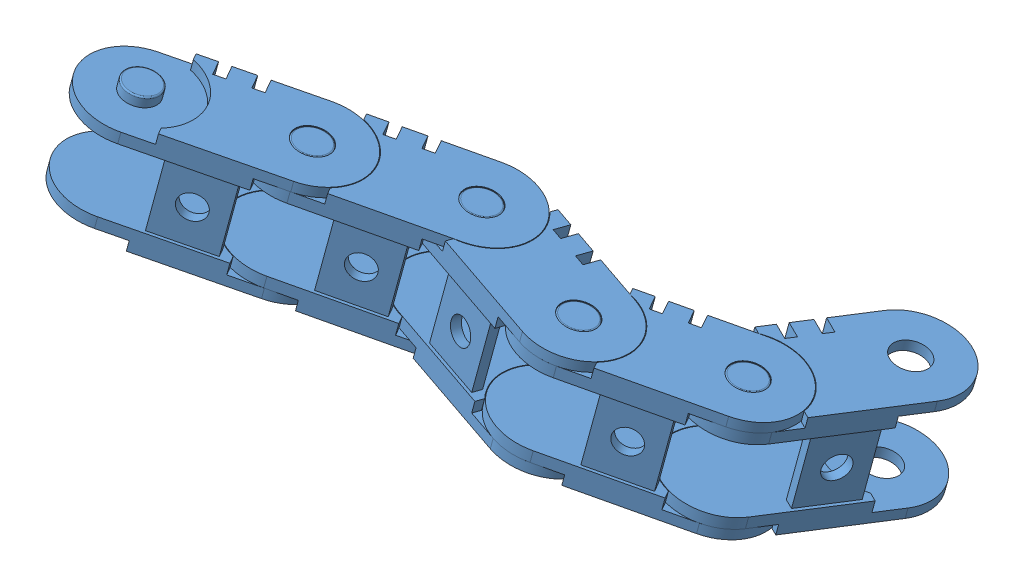
SolidWorks assembly energy chain, configuration Default. Lengths in mm.
Overall size (69.44 28.58 44.53).
5 component instances, 1 part files, 12 mates.
Components (placement in the parent):
- clen-6: clen [25x25] at (186.9346 0.4936 -8.835) x (0.848324 -0.220855 -0.481216) z (0.486505 -0.033523 0.873034) size (32.4 16.08 14)
- clen-7: clen [25x25] at (198.6906 -2.5591 -15.4058) x (0.853174 -0.221181 -0.472412) z (0.47795 -0.031301 0.877829) size (32.4 16.08 14)
- clen-8: clen [25x25] at (211.9978 -5.4844 -16.3032) x (0.960789 -0.189554 0.202369) z (-0.182278 0.118195 0.976117) size (32.4 16.08 14)
- clen-9: clen [25x25] at (223.7233 -8.2272 -19.1324) x (0.853174 -0.221181 -0.472412) z (0.47795 -0.031301 0.877829) size (32.4 16.08 14)
- clen-10: clen [25x25] at (230.7937 -10.5439 -29.0146) x (0.346349 -0.149315 -0.926147) z (0.91454 -0.16615 0.368795) size (32.4 16.08 14)
Mates (geometry in assembly coordinates):
- Concentric6: concentric anti-aligned: cylinder of clen-6 through (189.7699 -10.7257 -9.7667) axis (-0.208946 -0.97473 0.079009) radius 1.8075; cylinder of clen-7 through (189.5442 -11.7787 -9.6813) axis (0.208946 0.97473 -0.079009) radius 1.8
- Coincident12: coincident aligned: plane of clen-6 through (178.063 -7.6782 -3.1259) normal (0.208946 0.97473 -0.079009); plane of clen-7 through (189.7698 -10.726 -9.7666) normal (0.208946 0.97473 -0.079009)
- LimitAngle6: limit planar angle = 0.010056 rad aligned: plane of clen-6 through (175.5088 -7.5022 -7.7093) normal (-0.486505 0.033523 -0.873034); plane of clen-7 through (187.2606 -10.5616 -14.3752) normal (-0.47795 0.031301 -0.877829)
- Concentric7: concentric anti-aligned: cylinder of clen-7 through (201.5437 -13.778 -16.2859) axis (-0.208946 -0.97473 0.079009) radius 1.8075; cylinder of clen-8 through (201.318 -14.831 -16.2006) axis (0.208946 0.97473 -0.079009) radius 1.8
- Coincident13: coincident aligned: plane of clen-7 through (189.7698 -10.726 -9.7666) normal (0.208946 0.97473 -0.079009); plane of clen-8 through (201.5436 -13.7783 -16.2859) normal (0.208946 0.97473 -0.079009)
- LimitAngle7: limit planar angle = 0.698132 rad aligned: plane of clen-7 through (187.2606 -10.5616 -14.3752) normal (-0.47795 0.031301 -0.877829); plane of clen-8 through (202.5006 -14.3988 -21.4105) normal (0.182278 -0.118195 -0.976117)
- Concentric8: concentric anti-aligned: cylinder of clen-8 through (214.8026 -16.3938 -13.4933) axis (-0.208946 -0.97473 0.079009) radius 1.8075; cylinder of clen-9 through (214.5769 -17.4468 -13.4079) axis (0.208946 0.97473 -0.079009) radius 1.8
- Coincident14: coincident aligned: plane of clen-8 through (201.5436 -13.7783 -16.2859) normal (0.208946 0.97473 -0.079009); plane of clen-9 through (214.8025 -16.3941 -13.4932) normal (0.208946 0.97473 -0.079009)
- LimitAngle8: limit planar angle = 0.698132 rad aligned: plane of clen-8 through (202.5006 -14.3988 -21.4105) normal (0.182278 -0.118195 -0.976117); plane of clen-9 through (212.2933 -16.2298 -18.1018) normal (-0.47795 0.031301 -0.877829)
- Concentric9: concentric anti-aligned: cylinder of clen-9 through (226.5764 -19.4461 -20.0125) axis (-0.208946 -0.97473 0.079009) radius 1.8075; cylinder of clen-10 through (226.3507 -20.4991 -19.9272) axis (0.208946 0.97473 -0.079009) radius 1.8
- Coincident15: coincident aligned: plane of clen-9 through (214.8025 -16.3941 -13.4932) normal (0.208946 0.97473 -0.079009); plane of clen-10 through (226.5763 -19.4464 -20.0125) normal (0.208946 0.97473 -0.079009)
- LimitAngle9: limit planar angle = 0.698132 rad aligned: plane of clen-9 through (212.2933 -16.2298 -18.1018) normal (-0.47795 0.031301 -0.877829); plane of clen-10 through (221.775 -18.5741 -21.9487) normal (-0.91454 0.16615 -0.368795)
